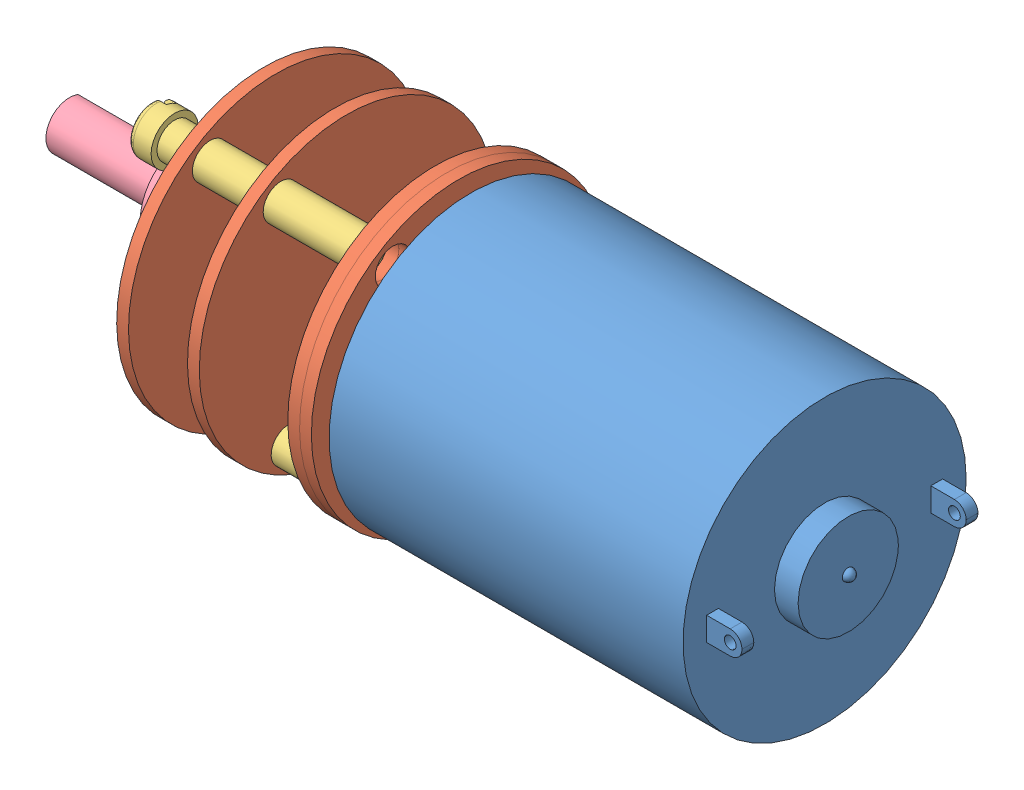
SolidWorks assembly MotorMFAWithoutSquare, configuration Défaut. Lengths in mm.
Overall size (67 25.91 25.97).
9 component instances, 4 part files, 19 mates.
Components (placement in the parent):
- Body-1: Body [Défaut] at (1.1106 0.6805 31.69) size (33 24 24)
- Plate-1: Plate [Défaut] at (-30.8894 0.6805 31.69) x (1 0 0) z (0 0.999306 0.037242) size (1 25 25)
- Plate-2: Plate [Défaut] at (-31.8894 0.6805 31.69) x (1 0 0) z (0 0.999306 0.037242) size (1 25 25)
- Plate-3: Plate [Défaut] at (-40.3894 0.6805 31.69) x (1 0 0) z (0 0.999306 0.037242) size (1 25 25)
- Plate-4: Plate [Défaut] at (-46.3894 0.6805 31.69) x (1 0 0) z (0 0.999306 0.037242) size (1 25 25)
- Screw-4: Screw [Défaut] at (-31.8894 9.572 37.275) x (0 0.394119 0.91906) z (0 -0.91906 0.394119) size (4 18.53 4)
- Screw-5: Screw [Défaut] at (-31.8894 1.0716 21.1973) x (0 0.311952 0.950098) z (0 -0.950098 0.311952) size (4 18.53 4)
- Screw-6: Screw [Défaut] at (-31.8894 -8.602 36.5977) x (0 0.055415 0.998463) z (0 -0.998463 0.055415) size (4 18.53 4)
- MFARotor-1: MFARotor [Défaut] at (-46.3894 0.6805 31.69) x (-1 0 0) z (0 -0.886864 -0.46203) size (16.5 8 8)
Mates (geometry in assembly coordinates):
- Coaxiale3: concentric aligned: cylinder of Plate-1 through (-29.8894 0.6805 31.69) axis (-1 0 0) radius 12.5; cylinder of Plate-2 through (-30.8894 0.6805 31.69) axis (-1 0 0) radius 12.5
- Coaxiale4: concentric aligned: cylinder of Plate-2 through (-30.8894 0.6805 31.69) axis (-1 0 0) radius 12.5; cylinder of Plate-3 through (-39.3894 0.6805 31.69) axis (-1 0 0) radius 12.5
- Coaxiale5: concentric aligned: cylinder of Plate-3 through (-39.3894 0.6805 31.69) axis (-1 0 0) radius 12.5; cylinder of Plate-4 through (-45.3894 0.6805 31.69) axis (-1 0 0) radius 12.5
- Coaxiale6: concentric aligned: cylinder of Plate-1 through (-30.8894 1.0716 21.1973) axis (1 0 0) radius 1.5; cylinder of Plate-2 through (-31.8894 1.0716 21.1973) axis (1 0 0) radius 1.5
- Coaxiale7: concentric aligned: cylinder of Plate-2 through (-31.8894 1.0716 21.1973) axis (1 0 0) radius 1.5; cylinder of Plate-3 through (-40.3894 1.0716 21.1973) axis (1 0 0) radius 1.5
- Coaxiale8: concentric aligned: cylinder of Plate-3 through (-40.3894 1.0716 21.1973) axis (1 0 0) radius 1.5; cylinder of Plate-4 through (-46.3894 1.0716 21.1973) axis (1 0 0) radius 1.5
- Coïncidente4: coincident anti-aligned: plane of Plate-1 through (-30.8894 0.6805 31.69) normal (-1 0 0); plane of Plate-2 through (-30.8894 0.6805 31.69) normal (1 0 0)
- Distance1: distance = 5 mm anti-aligned: plane of Plate-3 through (-40.3894 0.6805 31.69) normal (-1 0 0); plane of Plate-4 through (-45.3894 0.6805 31.69) normal (1 0 0)
- Distance3: distance = 2 mm anti-aligned: plane of Plate-4 through (-46.3894 0.6805 31.69) normal (-1 0 0); plane of Screw-4 through (-48.3894 9.572 37.275) normal (1 0 0)
- Distance4: distance = 2 mm anti-aligned: plane of Plate-4 through (-46.3894 0.6805 31.69) normal (-1 0 0); plane of Screw-5 through (-48.3894 1.0716 21.1973) normal (1 0 0)
- Distance6: distance = 2 mm anti-aligned: plane of Plate-4 through (-46.3894 0.6805 31.69) normal (-1 0 0); plane of Screw-6 through (-48.3894 -8.602 36.5977) normal (1 0 0)
- Coaxiale12: concentric: cylinder of Plate-4 through (-46.3894 -8.602 36.5977) axis (1 0 0) radius 1.5; cylinder of Screw-6 through (-46.3894 -8.602 36.5977) axis (1 0 0) radius 1.5
- Coaxiale13: concentric aligned: cylinder of Plate-4 through (-46.3894 1.0716 21.1973) axis (1 0 0) radius 1.5; cylinder of Screw-5 through (-48.3894 1.0716 21.1973) axis (1 0 0) radius 1.5
- Coaxiale14: concentric aligned: cylinder of Plate-4 through (-46.3894 9.572 37.275) axis (1 0 0) radius 1.5; cylinder of Screw-4 through (-48.3894 9.572 37.275) axis (1 0 0) radius 1.5
- Coïncidente14: coincident aligned: plane of Plate-4 through (-46.3894 0.6805 31.69) normal (-1 0 0); circle of MFARotor-1
- Coaxiale15: concentric anti-aligned: cylinder of Plate-4 through (-45.3894 0.6805 31.69) axis (-1 0 0) radius 12.5; cylinder of MFARotor-1 through (-52.8894 0.6805 31.69) axis (1 0 0) radius 4
- Distance2: distance = 1 mm anti-aligned: plane of Plate-1 through (-29.8894 0.6805 31.69) normal (1 0 0); plane of Body-1 through (-28.8894 0.6805 31.69) normal (-1 0 0)
- Coaxiale16: concentric anti-aligned: cylinder of Body-1 through (-28.8894 0.6805 31.69) axis (1 0 0) radius 12; cylinder of Plate-1 through (-29.8894 0.6805 31.69) axis (-1 0 0) radius 12.5
- Distance5: distance = 15.5 mm aligned: plane of Plate-4 through (-45.3894 0.6805 31.69) normal (1 0 0); plane of Plate-1 through (-29.8894 0.6805 31.69) normal (1 0 0)
